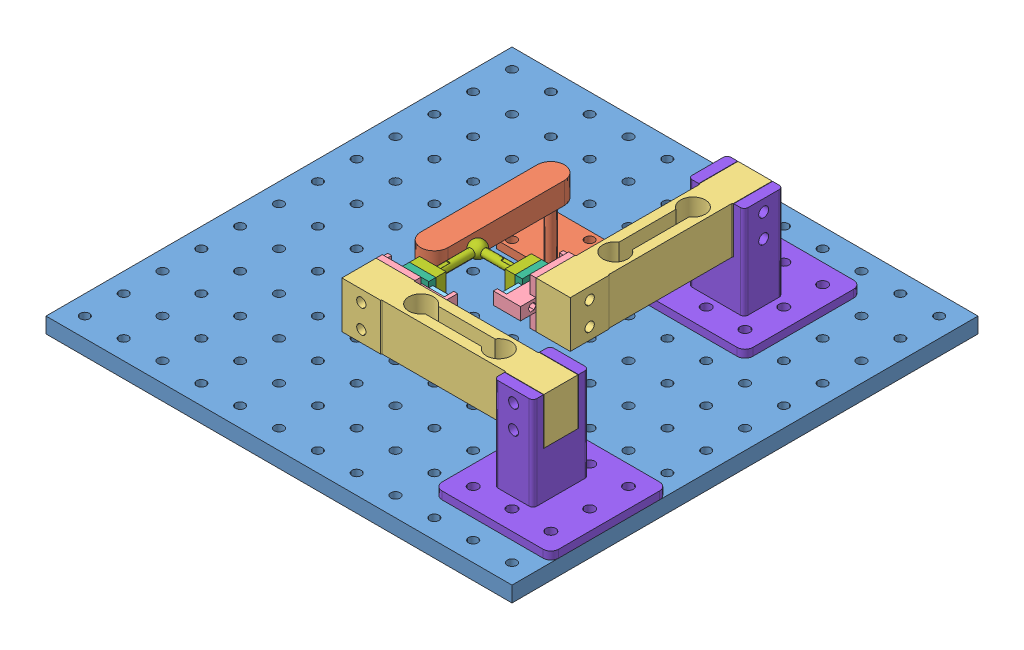
SolidWorks assembly ASM, configuration 기본. Lengths in mm.
Overall size (300 75 300).
13 component instances, 8 part files, 40 mates.
Components (placement in the parent):
- platform-1: platform [기본] at (65.8287 33.6876 394.83) size (300 10 300)
- finger_model-1: finger_model [기본] at (53.3287 43.6876 357.33) size (60 55 113.75)
- Loadcell-1: Loadcell [기본] at (128.3287 78.6876 365.83) x (0 0 -1) z (0 1 0) size (130 22 30)
- linear_guide_holder-1: linear_guide_holder [기본] at (117.3287 93.6876 418.33) x (0 0 1) z (-1 0 0) size (45 30 17.5)
- linear_guide_part1-1: linear_guide_part1 [기본] at (101.8287 93.6876 418.33) x (0 0 1) z (0 1 0) size (40 4 5)
- linear_guide_part2-1: linear_guide_part2 [기본] at (104.4287 93.6876 418.33) x (0 0 1) z (0 -1 0) size (17 4.6 12)
- contact_part-1: contact_part [기본] at (67.3287 93.6876 418.33) x (-1 0 0) z (0 -1 0) size (41 44 12)
- Loadcell-2: Loadcell [기본] at (119.8287 78.6876 482.33) x (1 0 0) z (0 1 0) size (130 22 30)
- linear_guide_holder-2: linear_guide_holder [기본] at (67.3287 93.6876 471.33) x (-1 0 0) z (0 0 -1) size (45 30 17.5)
- linear_guide_part1-2: linear_guide_part1 [기본] at (67.3287 93.6876 455.83) x (1 0 0) z (0 -1 0) size (40 4 5)
- linear_guide_part2-2: linear_guide_part2 [기본] at (67.3287 93.6876 458.43) x (1 0 0) z (0 1 0) size (17 4.6 12)
- Loadcell_holder_v3-1: Loadcell_holder_v3 [기본] at (128.3287 43.6876 307.33) size (75 65 75)
- Loadcell_holder_v3-2: Loadcell_holder_v3 [기본] at (178.3287 43.6876 482.33) x (0 0 1) z (-1 0 0) size (75 65 75)
Mates (geometry in assembly coordinates):
- 일치1: coincident anti-aligned: plane of platform-1 through (65.8287 43.6876 394.83) normal (0 1 0); plane of finger_model-1 through (53.3287 43.6876 357.33) normal (0 -1 0)
- 일치5: coincident anti-aligned: plane of Loadcell-1 through (117.3287 108.6876 430.83) normal (-1 0 0); plane of linear_guide_holder-1 through (117.3287 93.6876 418.33) normal (1 0 0)
- 동심13: concentric anti-aligned: cylinder of Loadcell-1 through (147.814 86.1876 418.33) axis (-1 0 0) radius 3; cylinder of linear_guide_holder-1 through (113.3287 86.1876 418.33) axis (1 0 0) radius 3.2
- 동심14: concentric anti-aligned: cylinder of Loadcell-1 through (147.814 101.1876 418.33) axis (-1 0 0) radius 3; cylinder of linear_guide_holder-1 through (113.3287 101.1876 418.33) axis (1 0 0) radius 3.2
- 일치13: coincident anti-aligned: plane of linear_guide_holder-1 through (105.8287 93.6876 418.33) normal (-1 0 0); plane of linear_guide_part1-1 through (105.8287 93.6876 418.33) normal (1 0 0)
- 동심19: concentric anti-aligned: cylinder of linear_guide_holder-1 through (105.8287 93.6876 403.33) axis (1 0 0) radius 1.15; cylinder of linear_guide_part1-1 through (105.8287 93.6876 403.33) axis (-1 0 0) radius 1.25
- 동심20: concentric anti-aligned: cylinder of linear_guide_holder-1 through (105.8287 93.6876 433.33) axis (1 0 0) radius 1.15; cylinder of linear_guide_part1-1 through (105.8287 93.6876 433.33) axis (-1 0 0) radius 1.25
- 일치14: coincident anti-aligned: plane of linear_guide_part1-1 through (101.8287 93.6876 418.33) normal (-1 0 0); plane of linear_guide_part2-1 through (101.8287 93.6876 418.33) normal (1 0 0)
- 일치15: coincident anti-aligned: plane of linear_guide_part1-1 through (105.8287 91.1876 438.33) normal (0 -1 0); plane of linear_guide_part2-1 through (122.1487 91.1876 426.83) normal (0 1 0)
- 거리 한도1: limit distance = 11.5 mm anti-aligned: plane of linear_guide_part2-1 through (99.8287 99.6876 426.83) normal (0 0 1); plane of linear_guide_holder-1 through (99.8287 97.6876 438.33) normal (0 0 -1)
- 거리 한도2: limit distance = 11.5 mm anti-aligned: plane of linear_guide_part2-1 through (99.8287 99.6876 409.83) normal (0 0 -1); plane of linear_guide_holder-1 through (99.8287 97.6876 398.33) normal (0 0 1)
- 동심21: concentric anti-aligned: cylinder of linear_guide_part2-1 through (101.8287 97.4376 418.33) axis (-1 0 0) radius 1; cylinder of contact_part-1 through (93.3287 97.4376 418.33) axis (1 0 0) radius 1.15
- 동심22: concentric anti-aligned: cylinder of linear_guide_part2-1 through (101.8287 89.9376 418.33) axis (-1 0 0) radius 1; cylinder of contact_part-1 through (93.3287 89.9376 418.33) axis (1 0 0) radius 1.15
- 너비2: width aligned: plane of linear_guide_holder-1 through (99.8287 97.6876 440.83) normal (0 0 1); plane of linear_guide_holder-1 through (99.8287 97.6876 395.83) normal (0 0 -1); plane of contact_part-1 through (93.3287 99.6876 426.83) normal (0 0 1); plane of contact_part-1 through (93.3287 99.6876 409.83) normal (0 0 -1)
- 일치22: coincident anti-aligned: plane of Loadcell-2 through (54.8287 108.6876 471.33) normal (0 0 -1); plane of linear_guide_holder-2 through (67.3287 93.6876 471.33) normal (0 0 1)
- 동심25: concentric anti-aligned: cylinder of Loadcell-2 through (67.3287 86.1876 501.8152) axis (0 0 -1) radius 3; cylinder of linear_guide_holder-2 through (67.3287 86.1876 467.33) axis (0 0 1) radius 3.2
- 동심26: concentric anti-aligned: cylinder of Loadcell-2 through (67.3287 101.1876 501.8152) axis (0 0 -1) radius 3; cylinder of linear_guide_holder-2 through (67.3287 101.1876 467.33) axis (0 0 1) radius 3.2
- 일치23: coincident anti-aligned: plane of linear_guide_holder-2 through (67.3287 93.6876 459.83) normal (0 0 -1); plane of linear_guide_part1-2 through (67.3287 93.6876 459.83) normal (0 0 1)
- 동심27: concentric anti-aligned: cylinder of linear_guide_holder-2 through (82.3287 93.6876 459.83) axis (0 0 1) radius 1.15; cylinder of linear_guide_part1-2 through (82.3287 93.6876 459.83) axis (0 0 -1) radius 1.25
- 동심28: concentric anti-aligned: cylinder of linear_guide_holder-2 through (52.3287 93.6876 459.83) axis (0 0 1) radius 1.15; cylinder of linear_guide_part1-2 through (52.3287 93.6876 459.83) axis (0 0 -1) radius 1.25
- 일치24: coincident anti-aligned: plane of linear_guide_part1-2 through (87.3287 91.1876 459.83) normal (0 -1 0); plane of linear_guide_part2-2 through (75.8287 91.1876 476.15) normal (0 1 0)
- 일치25: coincident anti-aligned: plane of linear_guide_part1-2 through (67.3287 93.6876 455.83) normal (0 0 -1); plane of linear_guide_part2-2 through (67.3287 93.6876 455.83) normal (0 0 1)
- 거리 한도3: limit distance = 11.5 mm anti-aligned: plane of linear_guide_part2-2 through (58.8287 87.6876 453.83) normal (-1 0 0); plane of linear_guide_holder-2 through (47.3287 97.6876 453.83) normal (1 0 0)
- 거리 한도4: limit distance = 11.5 mm anti-aligned: plane of linear_guide_holder-2 through (87.3287 97.6876 453.83) normal (-1 0 0); plane of linear_guide_part2-2 through (75.8287 87.6876 453.83) normal (1 0 0)
- 너비4: width anti-aligned: plane of linear_guide_holder-2 through (87.3287 97.6876 453.83) normal (-1 0 0); plane of linear_guide_holder-2 through (47.3287 97.6876 453.83) normal (1 0 0); plane of linear_guide_part2-2 through (75.8287 87.6876 453.83) normal (1 0 0); plane of linear_guide_part2-2 through (58.8287 87.6876 453.83) normal (-1 0 0)
- 동심29: concentric anti-aligned: cylinder of contact_part-1 through (67.3287 97.4376 447.33) axis (0 0 1) radius 1.15; cylinder of linear_guide_part2-2 through (67.3287 97.4376 455.83) axis (0 0 -1) radius 1
- 동심30: concentric anti-aligned: cylinder of contact_part-1 through (67.3287 89.9376 447.33) axis (0 0 1) radius 1.15; cylinder of linear_guide_part2-2 through (67.3287 89.9376 455.83) axis (0 0 -1) radius 1
- 일치27: coincident anti-aligned: plane of contact_part-1 through (67.3287 93.6876 453.83) normal (0 0 1); plane of linear_guide_part2-2 through (67.3287 93.6876 453.83) normal (0 0 -1)
- 일치29: coincident anti-aligned: plane of linear_guide_part2-1 through (99.8287 93.6876 418.33) normal (-1 0 0); plane of contact_part-1 through (99.8287 93.6876 418.33) normal (1 0 0)
- 동심33: concentric aligned: cylinder of platform-1 through (78.3287 43.6876 332.33) axis (0 -1 0) radius 3; cylinder of finger_model-1 through (78.3287 48.6876 332.33) axis (0 -1 0) radius 3
- 동심34: concentric aligned: cylinder of platform-1 through (28.3287 43.6876 357.33) axis (0 -1 0) radius 3; cylinder of finger_model-1 through (28.3287 48.6876 357.33) axis (0 -1 0) radius 3
- 동심36: concentric anti-aligned: cylinder of platform-1 through (153.3287 43.6876 332.33) axis (0 -1 0) radius 3; cylinder of Loadcell_holder_v3-1 through (153.3287 34.6367 332.33) axis (0 1 0) radius 3.2
- 동심37: concentric anti-aligned: cylinder of platform-1 through (103.3287 43.6876 332.33) axis (0 -1 0) radius 3; cylinder of Loadcell_holder_v3-1 through (103.3287 34.6367 332.33) axis (0 1 0) radius 3.2
- 일치32: coincident anti-aligned: plane of platform-1 through (65.8287 43.6876 394.83) normal (0 1 0); plane of Loadcell_holder_v3-1 through (95.8287 43.6876 339.83) normal (0 -1 0)
- 일치33: coincident anti-aligned: plane of platform-1 through (65.8287 43.6876 394.83) normal (0 1 0); plane of Loadcell_holder_v3-2 through (145.8287 43.6876 449.83) normal (0 -1 0)
- 너비7: width aligned: plane of Loadcell-1 through (139.3287 108.6876 325.83) normal (1 0 0); plane of Loadcell-1 through (117.3287 108.6876 325.83) normal (-1 0 0); plane of Loadcell_holder_v3-1 through (117.0787 52.7924 300.83) normal (1 0 0); plane of Loadcell_holder_v3-1 through (139.5787 52.7924 300.83) normal (-1 0 0)
- 동심40: concentric anti-aligned: cylinder of Loadcell-1 through (147.814 86.1876 313.33) axis (-1 0 0) radius 3; cylinder of Loadcell_holder_v3-1 through (101.2777 86.1876 313.33) axis (1 0 0) radius 3.2
- 동심41: concentric anti-aligned: cylinder of Loadcell-1 through (147.814 101.1876 313.33) axis (-1 0 0) radius 3; cylinder of Loadcell_holder_v3-1 through (101.2777 101.1876 313.33) axis (1 0 0) radius 3.2
- 너비8: width anti-aligned: plane of Loadcell_holder_v3-2 through (184.8287 52.7924 471.08) normal (0 0 1); plane of Loadcell_holder_v3-2 through (184.8287 52.7924 493.58) normal (0 0 -1); plane of Loadcell-2 through (159.8287 108.6876 471.33) normal (0 0 -1); plane of Loadcell-2 through (159.8287 108.6876 493.33) normal (0 0 1)
- 동심45: concentric anti-aligned: cylinder of Loadcell-2 through (172.3287 86.1876 501.8152) axis (0 0 -1) radius 3; cylinder of Loadcell_holder_v3-2 through (172.3287 86.1876 455.279) axis (0 0 1) radius 3.2
